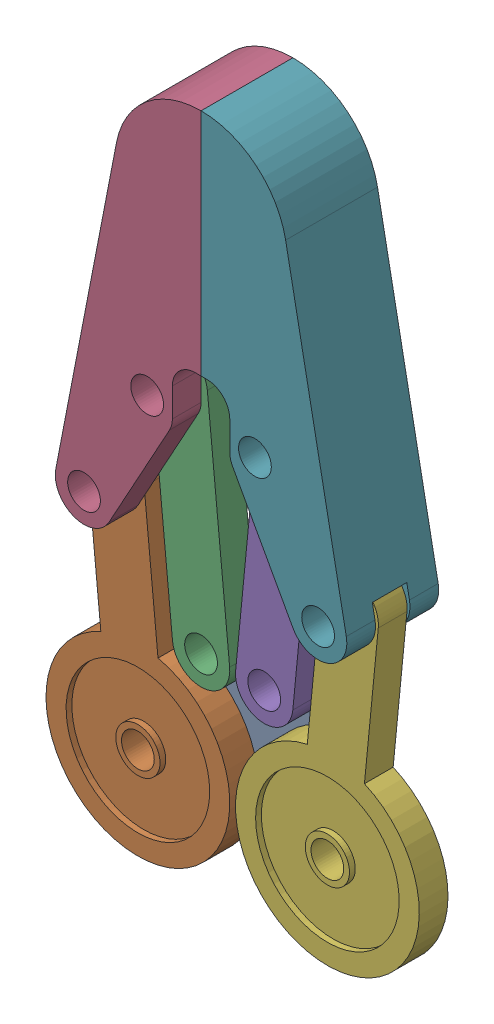
SolidWorks assembly Claw1 Q7, configuration Default. Lengths in mm.
Overall size (73.58 124.88 16).
7 component instances, 4 part files, 16 mates.
Components (placement in the parent):
- Arm_Plate-1: Arm_Plate [Default] at (16.3184 9.8304 30.4902) x (0 -1 0) z (0 0 1) size (32.5 45 1)
- Arm_Gear-1: Arm_Gear [Default] at (-2.1222 29.736 33.9902) x (0.097027 -0.995282 0) z (0 0 1) size (61 32 5)
- Arm_Link-1: Arm_Link [Default] at (8.8778 49.736 33.9902) x (0.097027 -0.995282 0) z (0 0 1) size (50 10 5)
- Grip-1: Grip [Default] at (16.3184 117.2321 41.9902) x (0 -1 0) z (0 0 -1) size (72.59 25.38 16)
- Arm_Link-2: Arm_Link [Default] at (23.7589 49.736 33.9902) x (-0.097027 -0.995282 0) z (0 0 1) size (50 10 5)
- Arm_Gear-2: Arm_Gear [Default] at (34.7589 29.736 33.9902) x (-0.097027 -0.995282 0) z (0 0 1) size (61 32 5)
- Grip-2: Grip [Default] at (16.3184 117.2321 25.9902) x (0 -1 0) z (0 0 1) size (72.59 25.38 16)
Mates (geometry in assembly coordinates):
- Coincident8: coincident anti-aligned: plane of Arm_Plate-1 through (16.3184 14.8304 31.4902) normal (0 0 1); plane of Arm_Gear-1 through (-4.0627 49.6417 31.4902) normal (0 0 -1)
- Coincident9: coincident anti-aligned: plane of Arm_Plate-1 through (16.3184 14.8304 31.4902) normal (0 0 1); plane of Arm_Gear-2 through (36.6995 49.6417 31.4902) normal (0 0 -1)
- Concentric10: concentric aligned: cylinder of Arm_Plate-1 through (32.8184 9.8304 31.4902) axis (0 0 -1) radius 2.85; cylinder of Arm_Gear-2 through (32.8184 9.8304 36.4902) axis (0 0 -1) radius 2.85
- Concentric11: concentric aligned: cylinder of Arm_Plate-1 through (-0.1816 9.8304 31.4902) axis (0 0 -1) radius 2.85; cylinder of Arm_Gear-1 through (-0.1816 9.8304 36.4902) axis (0 0 -1) radius 2.85
- Concentric12: concentric aligned: cylinder of Arm_Plate-1 through (10.8184 29.8304 31.4902) axis (0 0 -1) radius 2.85; cylinder of Arm_Link-1 through (10.8184 29.8304 36.4902) axis (0 0 -1) radius 2.85
- Coincident11: coincident anti-aligned: plane of Arm_Plate-1 through (16.3184 14.8304 31.4902) normal (0 0 1); plane of Arm_Link-1 through (6.9373 69.6417 31.4902) normal (0 0 -1)
- Concentric13: concentric aligned: cylinder of Arm_Plate-1 through (21.8184 29.8304 31.4902) axis (0 0 -1) radius 2.85; cylinder of Arm_Link-2 through (21.8184 29.8304 36.4902) axis (0 0 -1) radius 2.85
- Coincident12: coincident anti-aligned: plane of Arm_Plate-1 through (16.3184 14.8304 31.4902) normal (0 0 1); plane of Arm_Link-2 through (25.6995 69.6417 31.4902) normal (0 0 -1)
- Width3: width anti-aligned: plane of Arm_Link-1 through (6.9373 69.6417 36.4902) normal (0 0 1); plane of Grip-1 through (6.9373 69.6417 31.4902) normal (0 0 -1); plane of Arm_Link-1 through (15.3184 73.2321 36.9902) normal (0 0 -1); plane of Grip-1 through (-46.4889 44.6417 30.9902) normal (0 0 1)
- Concentric14: concentric anti-aligned: cylinder of Arm_Gear-1 through (-4.0627 49.6417 36.4902) axis (0 0 -1) radius 2.85; cylinder of Grip-1 through (-4.0627 49.6417 36.9902) axis (0 0 1) radius 2.85
- Concentric15: concentric anti-aligned: cylinder of Arm_Link-1 through (6.9373 69.6417 36.4902) axis (0 0 -1) radius 2.85; cylinder of Grip-1 through (6.9373 69.6417 36.9902) axis (0 0 1) radius 2.85
- Width4: width aligned: plane of Arm_Gear-2 through (36.6995 49.6417 36.4902) normal (0 0 1); plane of Grip-2 through (36.6995 49.6417 31.4902) normal (0 0 -1); plane of Arm_Gear-2 through (17.3184 73.2321 30.9902) normal (0 0 1); plane of Grip-2 through (79.1256 44.6417 36.9902) normal (0 0 -1)
- Concentric16: concentric aligned: cylinder of Arm_Gear-2 through (36.6995 49.6417 36.4902) axis (0 0 -1) radius 2.85; cylinder of Grip-2 through (36.6995 49.6417 41.9902) axis (0 0 -1) radius 2.85
- Concentric17: concentric aligned: cylinder of Arm_Link-2 through (25.6995 69.6417 36.4902) axis (0 0 -1) radius 2.85; cylinder of Grip-2 through (25.6995 69.6417 41.9902) axis (0 0 -1) radius 2.85
- Coincident13: coincident anti-aligned: plane of Grip-1 through (22.7844 117.3372 25.9902) normal (1 0 0); plane of Grip-2 through (22.7844 116.0594 41.9902) normal (-1 0 0)
- Coincident14: coincident anti-aligned: line of Grip-1 through (16.3184 77.2321 25.9902) axis (0 0 1); line of Grip-2 through (16.3184 77.2321 41.9902) axis (0 0 -1)
